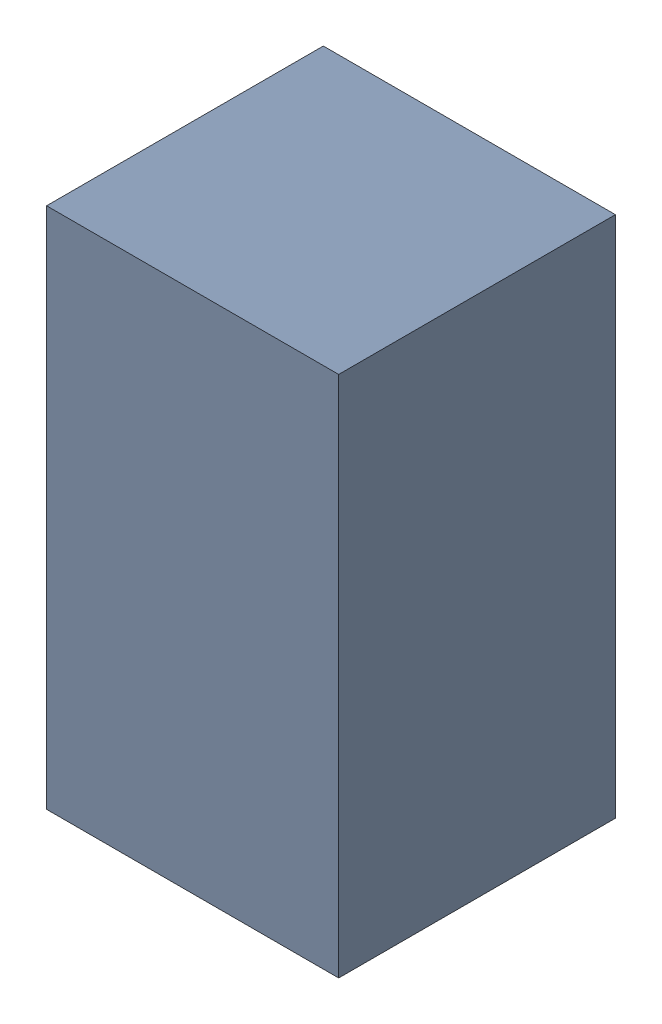
SolidWorks assembly R2_TDA4, configuration Standard. Lengths in mm.
Overall size (0.95 1.7 0.9).
2 component instances, 1 part files, 0 mates.
Components (placement in the parent):
- 885541560-1: 885541560 [Standard] at (6.08 -53.39 0) size (0.95 1.7 0.9)
  - Extruded_16-1: Extruded_16 [Standard] at origin size (0.95 1.7 0.9)
